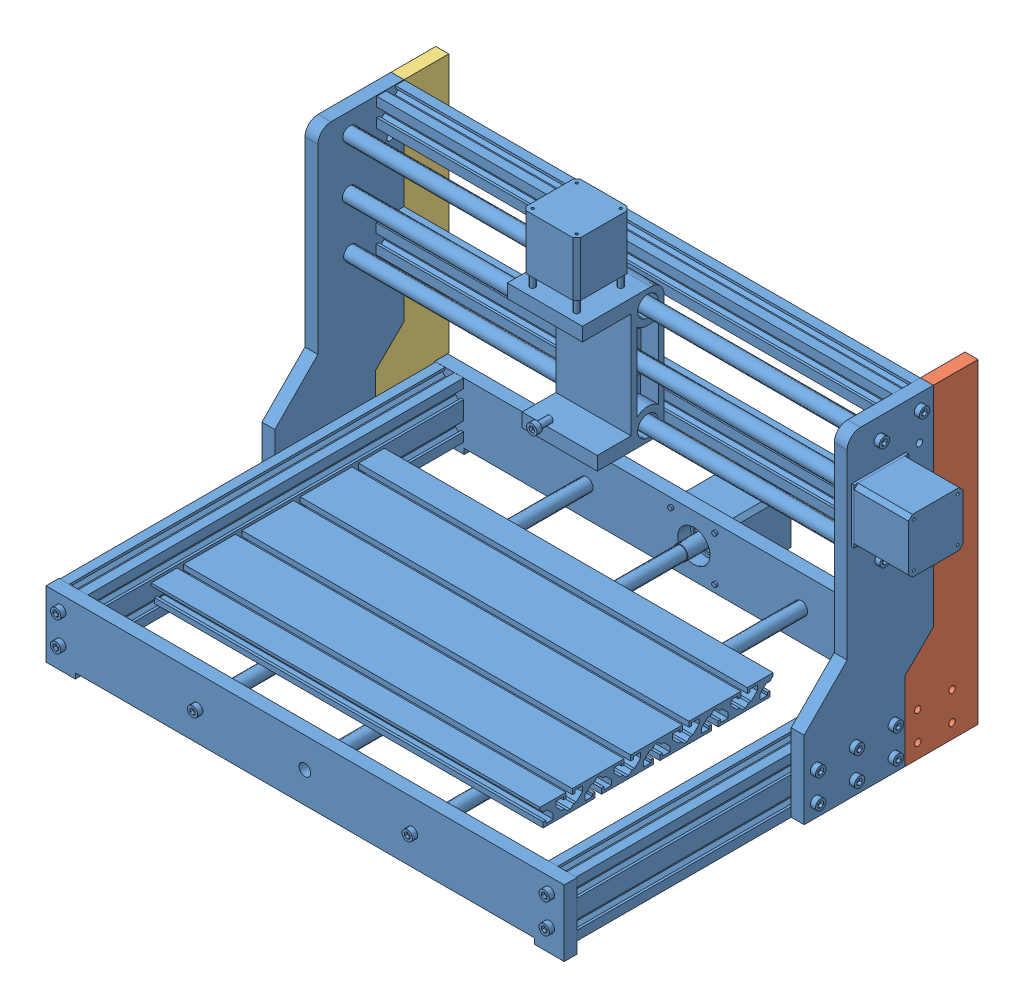
SolidWorks assembly Printer_Assem_v01, configuration Default. Lengths in mm.
Overall size (466.42 300.26 358).
3 component instances, 3 part files, 4 mates.
Components (placement in the parent):
- Closed_case_design-1: Closed_case_design [Default] at (-117.162 -55.8371 484.9481) x (1 0 0) z (0 1 0) size (466.42 358 300.26)
- Part2^Printer_Assem_v01-1: Part2^Printer_Assem_v01 [Default] at (378.9363 -55.8371 484.9481) x (0 -1 0) z (1 0 0) size (243.86 56.5 10) (virtual)
- MirrorPart2^Printer_Assem_v01-4: MirrorPart2^Printer_Assem_v01 [Default] at (-39.4148 -55.8371 484.9481) x (0 -1 0) z (1 0 0) size (243.86 56.5 10) (virtual)
Mates (geometry in assembly coordinates):
- InPlace1: in place: plane of Closed_case_design-1 through (378.9363 185.8537 315.6555) normal (1 0 0); plane of ? through (378.9363 0 0) normal (1 0 0); moOrthogonalPlaneRef_w of Closed_case_design-1 through (378.9363 185.8537 315.6555) normal (1 0 0); plane of ? through (378.9363 0 0) normal (0 1 0); plane of Closed_case_design-1 through (378.9363 185.8537 315.6555) normal (1 0 0); plane of ? through (378.9363 0 0) normal (0 0 -1); plane of Closed_case_design-1 through (378.9363 185.8537 315.6555) normal (1 0 0); unknown of Part2^Printer_Assem_v01-1
- Coincident1: coincident aligned: plane of Closed_case_design-1; plane of Part2^Printer_Assem_v01-1
- Coincident2: coincident aligned: moOrthogonalPlaneRef_w of Closed_case_design-1 through (378.9363 -55.8371 484.9481) normal (0 0 -1); plane of Part2^Printer_Assem_v01-1 through (378.9363 -55.8371 484.9481) normal (0 0 -1)
- Coincident3: coincident anti-aligned: moOrthogonalPlaneRef_w of Closed_case_design-1 through (378.9363 -55.8371 484.9481) normal (0 1 0); plane of Part2^Printer_Assem_v01-1 through (378.9363 -55.8371 484.9481) normal (0 -1 0)
